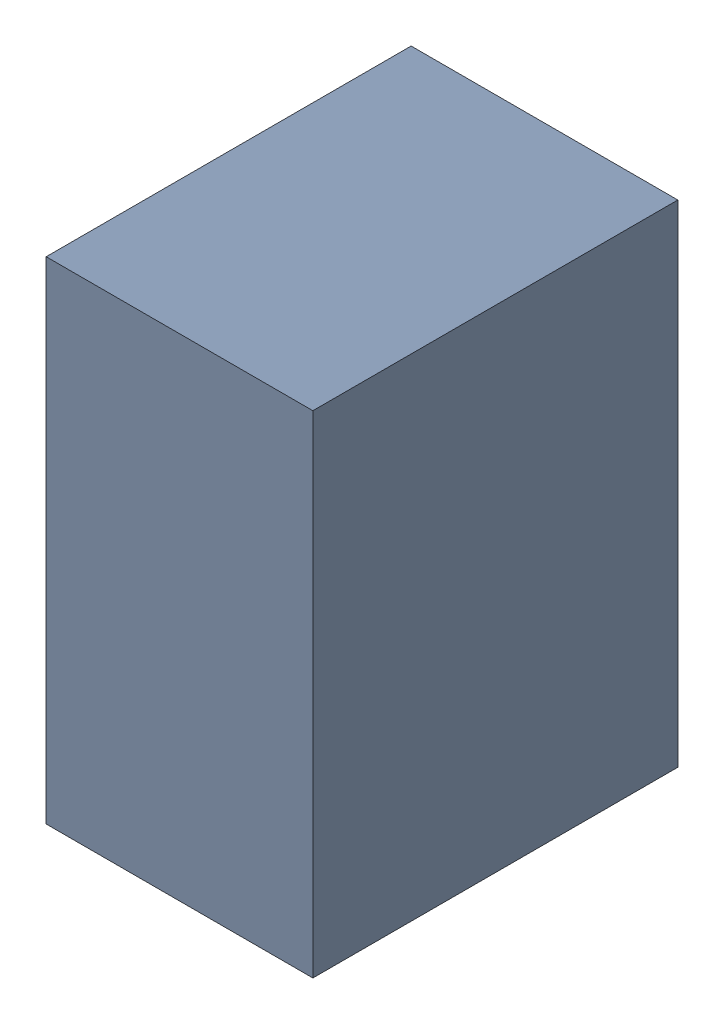
SolidWorks assembly C2, configuration Default. Lengths in mm.
Overall size (0.95 1.75 1.3).
2 component instances, 1 part files, 0 mates.
Components (placement in the parent):
- 4438511232-1: 4438511232 [Default] at (12.7 27.748 0) size (0.95 1.75 1.3)
  - Extruded_4-1: Extruded_4 [Default] at origin size (0.95 1.75 1.3)
